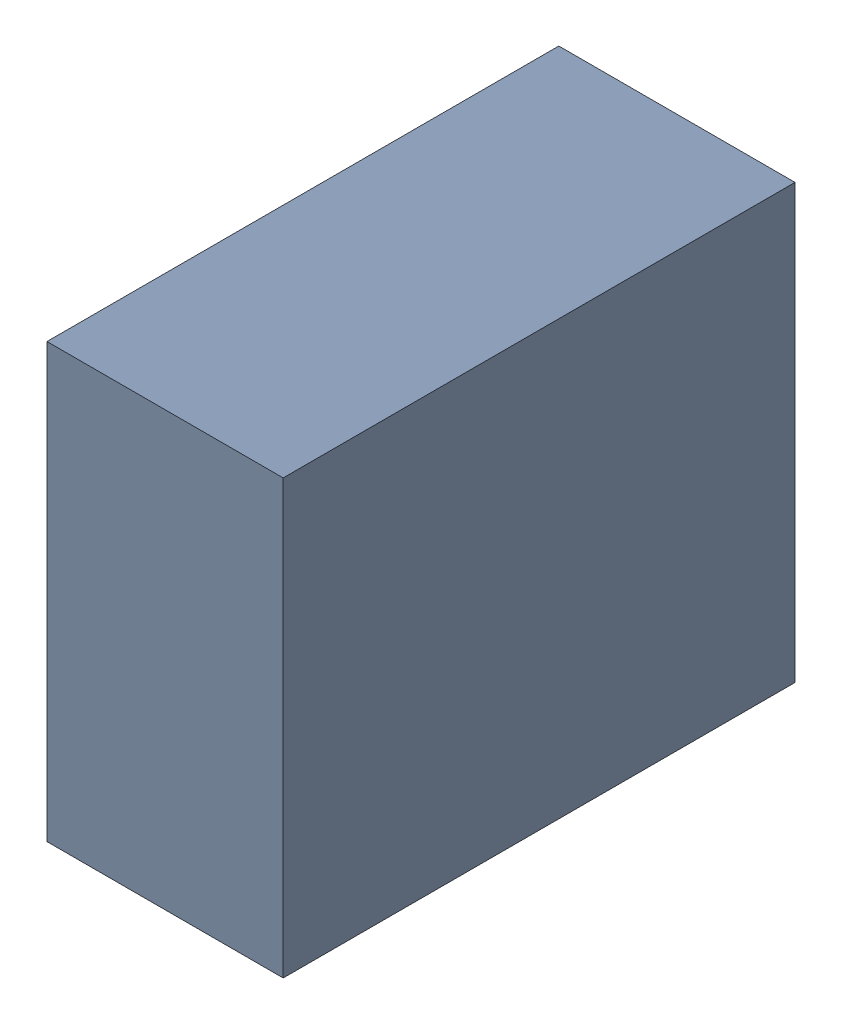
SolidWorks assembly C11, configuration Standard. Lengths in mm.
Overall size (0.6 1.1 1.3).
2 component instances, 1 part files, 0 mates.
Components (placement in the parent):
- 885542376-1: 885542376 [Standard] at (-22.66 -5.13 0) size (0.6 1.1 1.3)
  - Extruded_25-1: Extruded_25 [Standard] at origin size (0.6 1.1 1.3)
